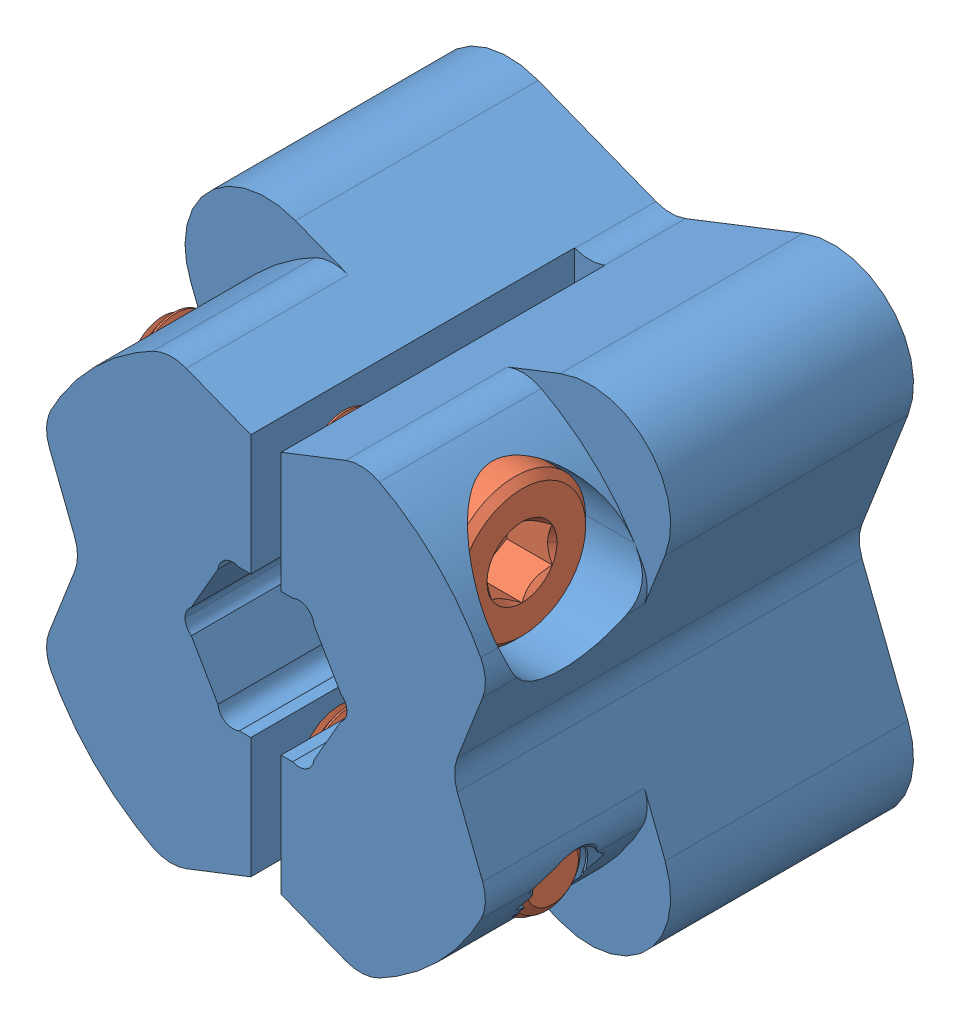
SolidWorks assembly 8mm Hex Hyper Hub 1310-0016-4008, configuration Default. Lengths in mm.
Overall size (24 24 22).
3 component instances, 2 part files, 0 mates.
Components (placement in the parent):
- 1310-0016-4008.STEP-1: 1310-0016-4008.STEP [Default] at (-15.4211 -5.7247 3.0261) size (24 24 22)
- 2800-0004-0014_90128A207.STEP-1: 2800-0004-0014_90128A207.STEP [Default] at (-25.1711 0.5753 18.6261) x (0 0 1) z (-1 0 0) size (7 7 18.01)
- 2800-0004-0014_90128A207.STEP-2: 2800-0004-0014_90128A207.STEP [Default] at (-5.6711 -12.0247 18.6261) x (0 0 1) z (1 0 0) size (7 7 18.01)
